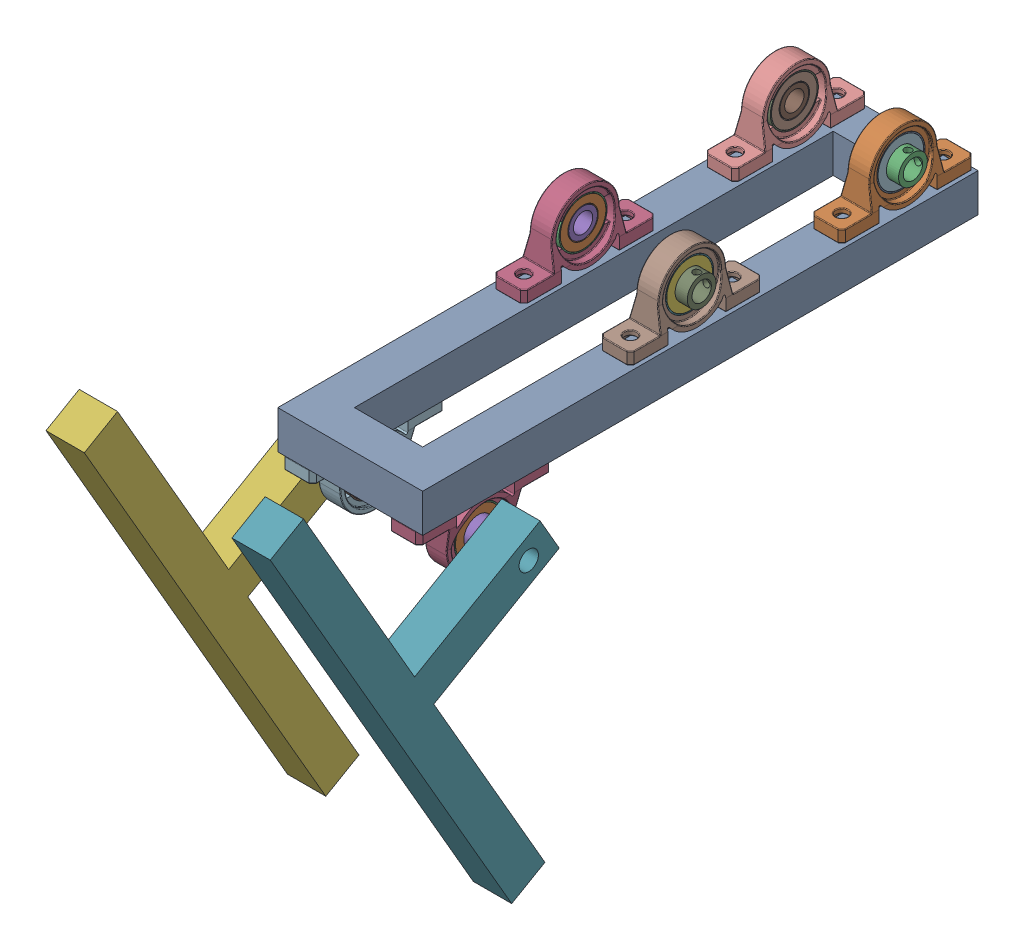
SolidWorks assembly Mirrorroller_tensioner, configuration Default. Lengths in mm.
Overall size (92.88 211.14 309.55).
9 component instances, 3 part files, 12 mates.
Components (placement in the parent):
- Mirrorroller_tensioner-1: Mirrorroller_tensioner [Default] at (-40.6979 7.0705 -11.2795) size (60 15.88 230)
- Mirror8mm İç Çap - Rulmanlı Yatak-1: Mirror8mm İç Çap - Rulmanlı Yatak [Varsayılan] at (-62.7604 22.9455 -11.2795) x (0 0 1) z (-1 0 0) size (55 28.5 15.02)
- Mirror8mm İç Çap - Rulmanlı Yatak-2: Mirror8mm İç Çap - Rulmanlı Yatak [Varsayılan] at (-18.6354 22.9455 -11.2795) x (0 0 -1) z (1 0 0) size (55 28.5 15.02)
- Mirror8mm İç Çap - Rulmanlı Yatak-3: Mirror8mm İç Çap - Rulmanlı Yatak [Varsayılan] at (-62.7604 7.0705 76.2205) x (0 0 -1) z (-1 0 0) size (55 28.5 15.02)
- Mirror8mm İç Çap - Rulmanlı Yatak-4: Mirror8mm İç Çap - Rulmanlı Yatak [Varsayılan] at (-18.6354 7.0705 76.2205) x (0 0 1) z (1 0 0) size (55 28.5 15.02)
- Mirrorroller_pivot-1: Mirrorroller_pivot [Default] at (-87.1354 -36.3983 126.3958) x (1 0 0) z (0 0.866025 0.5) size (15.88 75.88 200)
- Mirrorroller_pivot-2: Mirrorroller_pivot [Default] at (5.7396 -36.3983 126.3958) x (-1 0 0) z (0 -0.866025 -0.5) size (15.88 75.88 200)
- Mirror8mm İç Çap - Rulmanlı Yatak-5: Mirror8mm İç Çap - Rulmanlı Yatak [Varsayılan] at (-62.7604 22.9455 -98.7795) x (0 0 1) z (-1 0 0) size (55 28.5 15.02)
- Mirror8mm İç Çap - Rulmanlı Yatak-6: Mirror8mm İç Çap - Rulmanlı Yatak [Varsayılan] at (-18.6354 22.9455 -98.7795) x (0 0 -1) z (1 0 0) size (55 28.5 15.02)
Mates (geometry in assembly coordinates):
- Coincident1: coincident anti-aligned: plane of Mirrorroller_tensioner-1 through (-40.6979 22.9455 -11.2795) normal (0 1 0); plane of Mirror8mm İç Çap - Rulmanlı Yatak-1 through (-56.2604 22.9455 -38.7795) normal (0 -1 0)
- Width1: width anti-aligned: plane of Mirror8mm İç Çap - Rulmanlı Yatak-1 through (-56.2604 27.9455 -38.7795) normal (1 0 0); plane of Mirrorroller_tensioner-1 through (-69.2604 27.9455 -38.7795) normal (-1 0 0); plane of Mirror8mm İç Çap - Rulmanlı Yatak-1 through (-70.6979 22.9455 103.7205) normal (-1 0 0); plane of Mirrorroller_tensioner-1 through (-54.8229 22.9455 87.8455) normal (1 0 0)
- Coincident2: coincident aligned: plane of Mirrorroller_tensioner-1 through (-70.6979 22.9455 103.7205) normal (0 0 1); plane of Mirror8mm İç Çap - Rulmanlı Yatak-3 through (-62.7604 7.0705 103.7205) normal (0 0 1)
- Coincident3: coincident anti-aligned: plane of Mirrorroller_tensioner-1 through (-40.6979 7.0705 -11.2795) normal (0 -1 0); plane of Mirror8mm İç Çap - Rulmanlı Yatak-3 through (-56.2604 7.0705 103.7205) normal (0 1 0)
- Width2: width anti-aligned: plane of Mirror8mm İç Çap - Rulmanlı Yatak-3 through (-69.2604 2.0705 103.7205) normal (-1 0 0); plane of Mirrorroller_tensioner-1 through (-56.2604 2.0705 103.7205) normal (1 0 0); plane of Mirror8mm İç Çap - Rulmanlı Yatak-3 through (-54.8229 22.9455 87.8455) normal (1 0 0); plane of Mirrorroller_tensioner-1 through (-70.6979 22.9455 103.7205) normal (-1 0 0)
- Concentric1: concentric aligned: cylinder of Mirror8mm İç Çap - Rulmanlı Yatak-3 through (-71.2604 -7.4295 76.2205) axis (1 0 0) radius 4; cylinder of Mirrorroller_pivot-1 through (-87.1354 -7.4295 76.2205) axis (1 0 0) radius 4
- Coincident4: coincident anti-aligned: plane of Mirror8mm İç Çap - Rulmanlı Yatak-3 through (-71.2604 -7.4295 76.2205) normal (-1 0 0); plane of Mirrorroller_pivot-1 through (-71.2604 -36.3983 126.3958) normal (1 0 0)
- Width3: width anti-aligned: plane of Mirror8mm İç Çap - Rulmanlı Yatak-1 through (-62.7604 22.9455 16.2205) normal (0 0 1); plane of Mirrorroller_tensioner-1 through (-62.7604 22.9455 -38.7795) normal (0 0 -1); plane of Mirror8mm İç Çap - Rulmanlı Yatak-1 through (-70.6979 22.9455 -126.2795) normal (0 0 -1); plane of Mirrorroller_tensioner-1 through (-70.6979 22.9455 103.7205) normal (0 0 1)
- Angle1: planar angle = 1.047198 rad anti-aligned: plane of Mirrorroller_pivot-1 through (-71.2604 -32.4295 119.5217) normal (0 0.5 -0.866025); plane of Mirrorroller_tensioner-1 through (-40.6979 7.0705 -11.2795) normal (0 -1 0)
- Coincident5: coincident anti-aligned: plane of Mirrorroller_tensioner-1 through (-40.6979 22.9455 -11.2795) normal (0 1 0); plane of Mirror8mm İç Çap - Rulmanlı Yatak-5 through (-56.2604 22.9455 -126.2795) normal (0 -1 0)
- Width4: width anti-aligned: plane of Mirror8mm İç Çap - Rulmanlı Yatak-5 through (-69.2604 27.9455 -126.2795) normal (-1 0 0); plane of Mirrorroller_tensioner-1 through (-56.2604 27.9455 -126.2795) normal (1 0 0); plane of Mirror8mm İç Çap - Rulmanlı Yatak-5 through (-54.8229 22.9455 87.8455) normal (1 0 0); plane of Mirrorroller_tensioner-1 through (-70.6979 22.9455 103.7205) normal (-1 0 0)
- Coincident6: coincident aligned: plane of Mirrorroller_tensioner-1 through (-70.6979 22.9455 -126.2795) normal (0 0 -1); plane of Mirror8mm İç Çap - Rulmanlı Yatak-5 through (-62.7604 22.9455 -126.2795) normal (0 0 -1)
